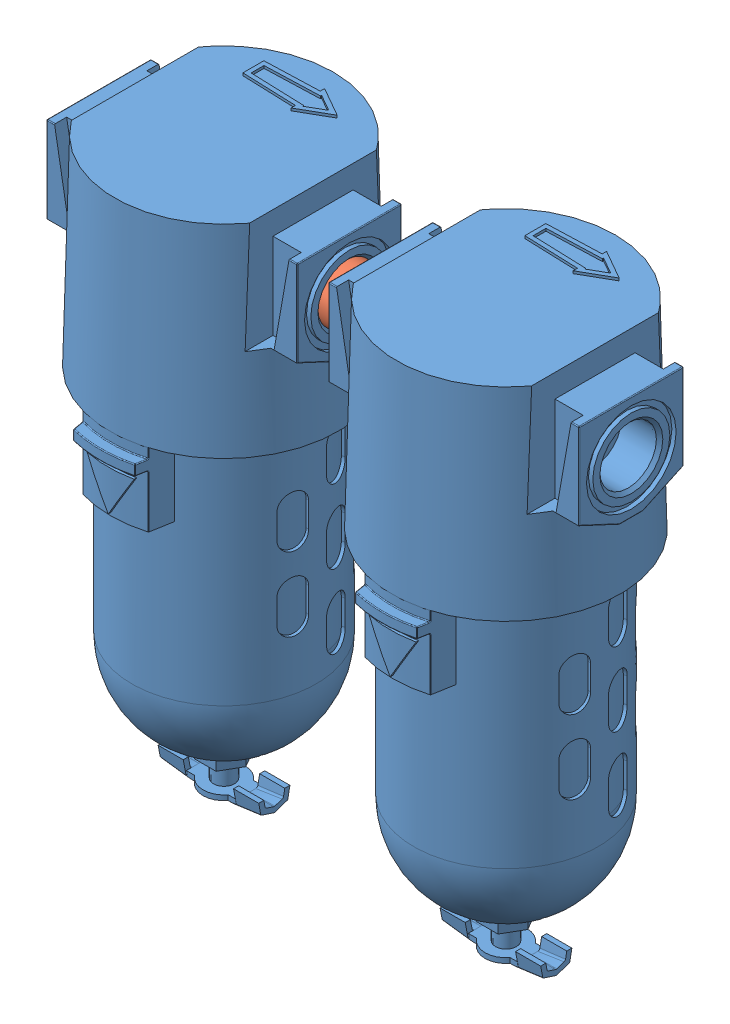
SolidWorks assembly ReadingTech_3P-020-P03-DCP, configuration Default. Lengths in mm.
Overall size (161.38 171.7 72.07).
3 component instances, 2 part files, 3 mates.
Components (placement in the parent):
- ReadingTech_3P-020-P03-P-1: ReadingTech_3P-020-P03-P [Default] at (-16.4376 104.2307 -5.7588) size (75.95 171.7 72.07)
- ReadingTech_3P-020-P03-P-2: ReadingTech_3P-020-P03-P [Default] at (68.9943 104.2307 -5.7588) size (75.95 171.7 72.07)
- ReadingTech- 20cfm_connector_.375in-1: ReadingTech- 20cfm_connector_.375in [Default] at (31.9933 81.3707 -5.7588) x (0 1 0) z (0 0 1) size (17.14 11.43 17.14)
Mates (geometry in assembly coordinates):
- Coincident1: coincident anti-aligned: circle of ReadingTech_3P-020-P03-P-1; circle of ReadingTech- 20cfm_connector_.375in-1
- Coincident2: coincident aligned: circle of ReadingTech_3P-020-P03-P-2; circle of ReadingTech- 20cfm_connector_.375in-1
- Coincident3: coincident aligned: plane of ReadingTech_3P-020-P03-P-1 through (-16.4376 104.2307 6.3824) normal (0 0 1); plane of ReadingTech_3P-020-P03-P-2 through (68.9943 104.2307 6.3824) normal (0 0 1)
